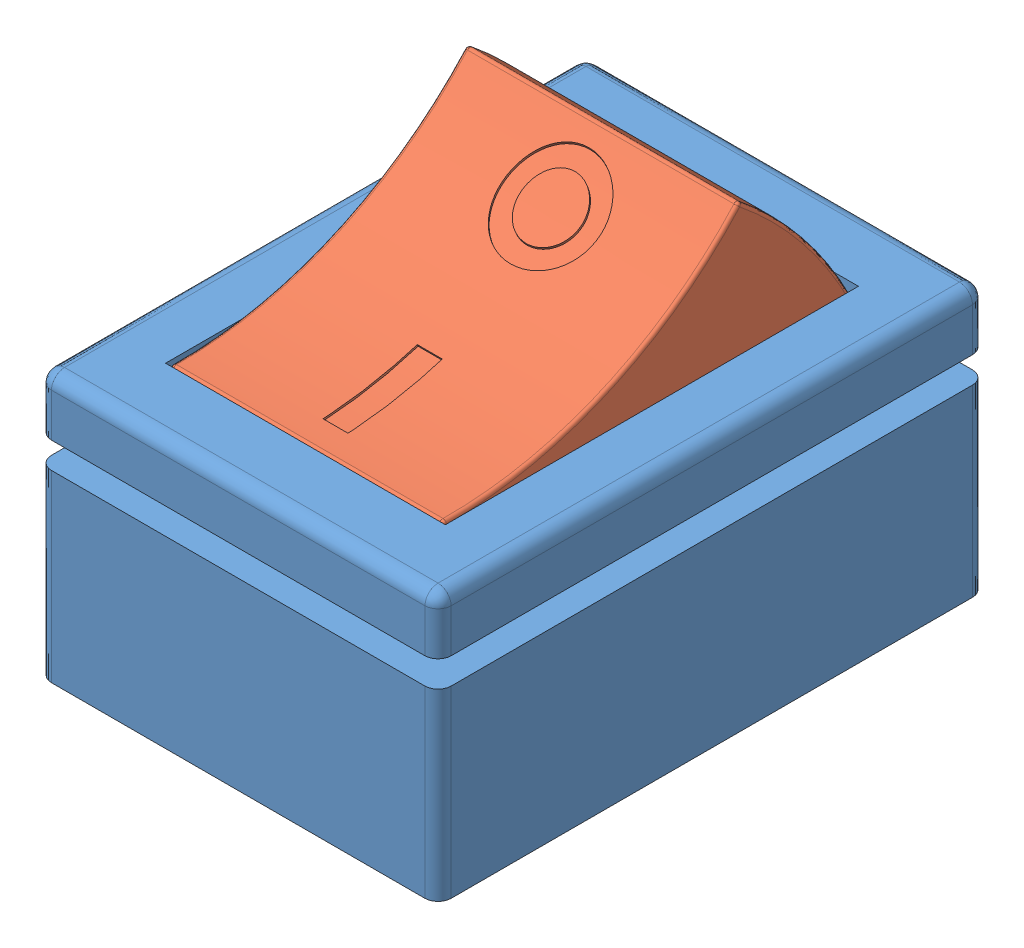
SolidWorks assembly Rocker Switch, configuration ON. Lengths in mm.
Overall size (15.24 15.79 20.88).
2 component instances, 2 part files, 4 mates.
Components (placement in the parent):
- Rocker Frame-1: Rocker Frame [Default] at (-53.0359 28.5292 21.437) size (15.24 10.16 20.88)
- Rocker-1: Rocker [Default] at (-45.4159 34.9852 10.4897) x (0 0.399929 -0.916546) z (1 0 0) size (15.99 6.69 12.55)
Mates (geometry in assembly coordinates):
- Concentric1: concentric anti-aligned: cylinder of Rocker Frame-1 through (-53.0359 36.1492 10.9976) axis (1 0 0) radius 0.25; cylinder of Rocker-1 through (-36.7743 36.1492 10.9976) axis (-1 0 0) radius 1.016
- Distance1: distance = 0.127 mm anti-aligned: plane of Rocker-1 through (-40.2089 53.4202 18.5337) normal (1 0 0); plane of Rocker Frame-1 through (-40.0819 38.6892 3.1236) normal (-1 0 0)
- Coincident25: coincident: plane of Rocker Frame-1 through (-53.0359 38.6892 21.437) normal (0 1 0); line of Rocker-1 through (-50.4959 38.6892 18.7075) axis (1 0 0)
- Coincident26: coincident: plane of Rocker Frame-1 through (-53.0359 38.6892 21.437) normal (0 1 0); line of Rocker-1 through (-40.3359 38.6892 3.2877) axis (-1 0 0)
